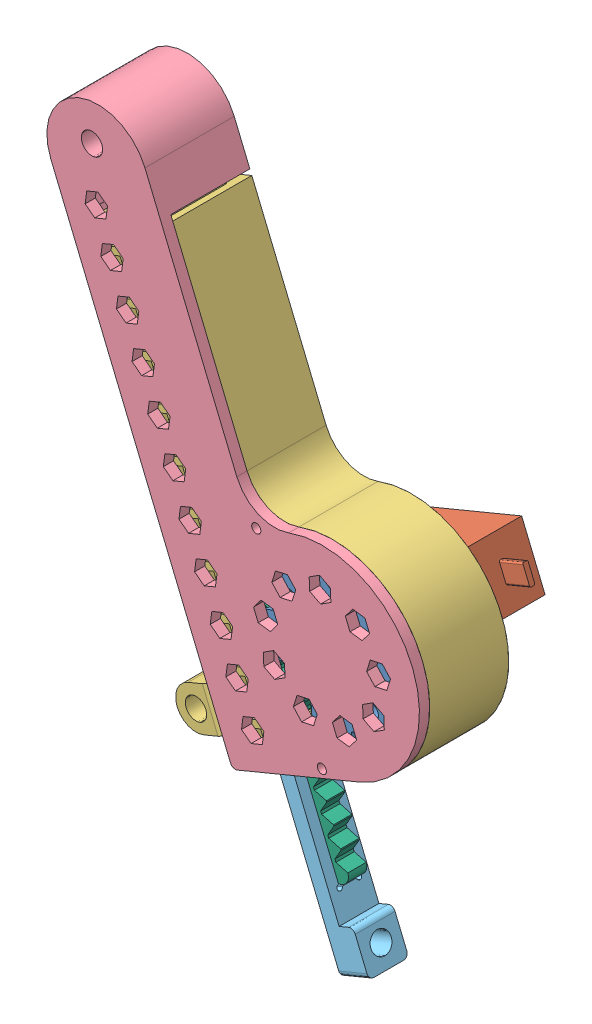
SolidWorks assembly MiniLinearServoV8, configuration Standard. Lengths in mm.
Overall size (82.06 139.86 35.6).
7 component instances, 6 part files, 13 mates.
Components (placement in the parent):
- Zahnrad_neu_32mmV2-1: Zahnrad_neu_32mmV2 [Standard] at (-43.7841 46.9905 -18.1912) x (-0.978242 -0.207467 0) z (0 0 -1) size (32.2 32.24 4.6)
- TowerServoSG92R-1: TowerServoSG92R [Standard] at (-48.5182 45.0274 -30.7912) x (0.923728 0.383049 0) z (0 0 1) size (32.2 12 29.65)
- BodyBase1-1: BodyBase1 [Standard] at (-43.992 46.9043 -21.9912) x (0.923728 0.383049 0) z (0 0 1) size (54 84 17.5)
- BodyTop1-2: BodyTop1 [Standard] at (-43.992 46.9043 -13.2412) x (-0.923728 -0.383049 0) z (0 0 -1) size (46 103 17.5)
- ZahnstangeKomplett-1: ZahnstangeKomplett [Standard] at (-77.8474 84.1665 -26.9167) x (-0.383049 0.923728 0) z (0.923728 0.383049 0) size (100 7.8 6)
  - Zahnstangenkörper-1: Zahnstangenkörper [Standard] at (-48.626 8.3754 -1.5) size (100 7.8 6)
  - ZahnstangenInlay-1: ZahnstangenInlay [Standard] at (-54.3114 8.2754 -3) x (1 0 0) z (0 -1 0) size (80 5.5 3.6)
Mates (geometry in assembly coordinates):
- Konzentrisch1: concentric aligned: cylinder of Zahnrad_neu_32mmV2-1 through (-43.7841 46.9905 -18.1912) axis (0 0 -1) radius 2.15; cylinder of TowerServoSG92R-1 through (-43.7841 46.9905 -18.1912) axis (0 0 -1) radius 2
- Deckungsgleich8: coincident anti-aligned: plane of TowerServoSG92R-1 through (-48.5182 45.0274 -29.7412) normal (0 0 1); plane of BodyBase1-1 through (-43.992 46.9043 -29.7412) normal (0 0 -1)
- Deckungsgleich10: coincident anti-aligned: plane of Zahnrad_neu_32mmV2-1 through (-43.7841 46.9905 -18.1912) normal (0 0 -1); plane of TowerServoSG92R-1 through (-43.7841 46.9905 -18.1912) normal (0 0 1)
- Abstand5: distance = 0.5 mm anti-aligned: plane of TowerServoSG92R-1 through (-61.0919 33.3179 -29.7412) normal (0.383049 -0.923728 0); plane of BodyBase1-1 through (-56.7436 34.5798 -29.7412) normal (-0.383049 0.923728 0)
- Abstand6: distance = 0.5 mm anti-aligned: plane of TowerServoSG92R-1 through (-61.0699 46.3179 -47.8412) normal (-0.923728 -0.383049 0); plane of BodyBase1-1 through (-61.7233 46.5882 -29.7412) normal (0.923728 0.383049 0)
- Deckungsgleich14: coincident anti-aligned: plane of BodyBase1-1 through (-43.992 46.9043 -14.2412) normal (0 0 1); plane of BodyTop1-2 through (-43.992 46.9043 -14.2412) normal (0 0 -1)
- Deckungsgleich15: coincident aligned: plane of BodyBase1-1 through (-68.9326 36.562 -14.2412) normal (-0.923728 -0.383049 0); plane of BodyTop1-2 through (-68.9326 36.562 -14.2412) normal (-0.923728 -0.383049 0)
- Deckungsgleich16: coincident anti-aligned: plane of BodyBase1-1 through (-87.7477 100.2094 -22.4412) normal (0.923728 0.383049 0); plane of ZahnstangeKomplett-1/Zahnstangenkörper-1 through (-61.9924 38.1001 -18.5412) normal (-0.923728 -0.383049 0)
- Deckungsgleich20: coincident anti-aligned: plane of BodyBase1-1 through (-87.7477 100.2094 -22.4412) normal (0.923728 0.383049 0); plane of ZahnstangeKomplett-1/Zahnstangenkörper-1 through (-61.9924 38.1001 -18.5412) normal (-0.923728 -0.383049 0)
- Deckungsgleich22: coincident anti-aligned: plane of BodyBase1-1 through (-43.992 46.9043 -22.4412) normal (0 0 1); plane of ZahnstangeKomplett-1/Zahnstangenkörper-1 through (-40.0688 -6.9372 -22.4412) normal (0 0 -1)
- Zahnstange/Ritzel-Verknüpfung4: rack pinion = 32.254 mm: line of ZahnstangeKomplett-1/Zahnstangenkörper-1 through (-77.9907 84.5119 -14.6412) axis (0.383049 -0.923728 0); cylinder of Zahnrad_neu_32mmV2-1 through (-43.7841 46.9905 -20.1912) axis (0 0 1) radius 16.127
- Deckungsgleich23: coincident aligned: plane of BodyBase1-1 through (-68.9326 36.562 -14.2412) normal (-0.923728 -0.383049 0); plane of BodyTop1-2 through (-68.9326 36.562 -14.2412) normal (-0.923728 -0.383049 0)
- Deckungsgleich24: coincident aligned: plane of BodyBase1-1 through (-36.714 29.3535 -14.2412) normal (0.383049 -0.923728 0); plane of BodyTop1-2 through (-36.714 29.3535 -14.2412) normal (0.383049 -0.923728 0)
